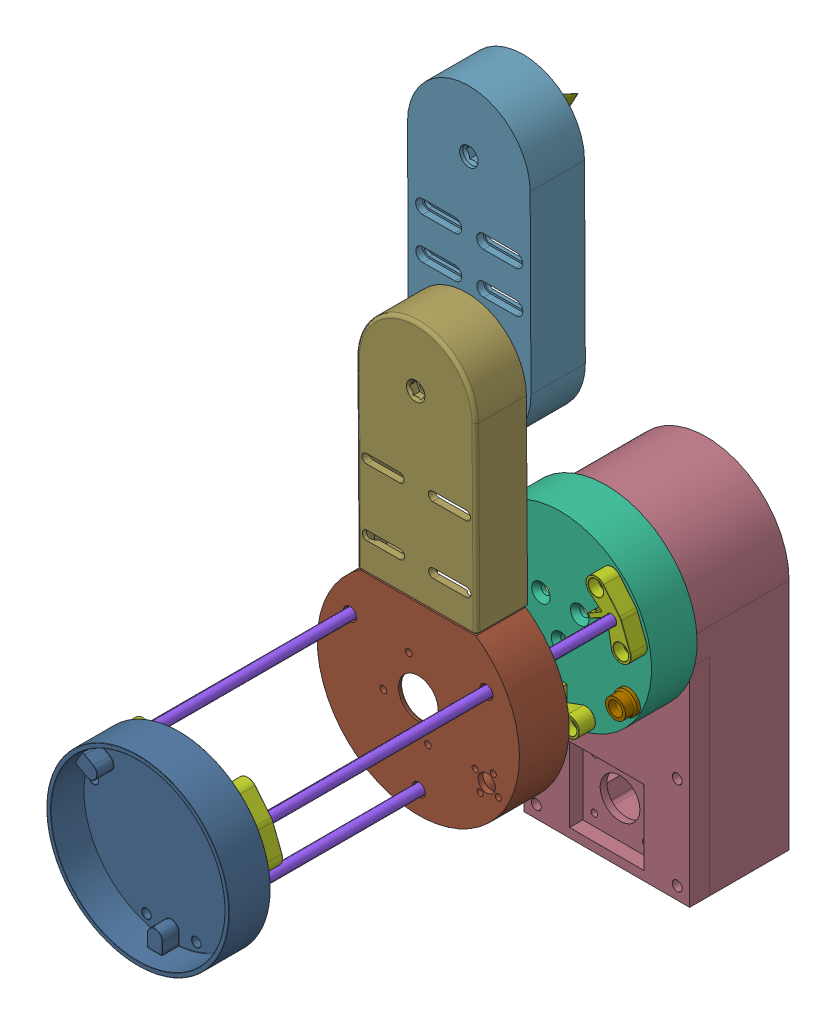
SolidWorks assembly Ensamblaje1 - copia, configuration Predeterminado. Lengths in mm.
Overall size (166.3 444.08 343).
26 component instances, 16 part files, 60 mates.
Components (placement in the parent):
- 4_Apoya rod rev2-1: 4_Apoya rod rev2 [Predeterminado] at (-2.0174 -4.7409 95) size (100 100 5)
- single direction thrust ball bearing_ks-1: single direction thrust ball bearing_ks [KS B 2022 ST - 51108-D] at (-2.0174 -4.7409 104.5) x (0.912212 -0.409718 0) z (0 0 -1) size (60 60 13)
- 3_sujeta_rod_sup rev2-1: 3_sujeta_rod_sup rev2 [Predeterminado] at (-2.0174 -4.7409 113) x (-0.50451 0.863406 0) z (0 0 -1) size (64 64 8)
- 4_Apoya rod rev2-2: 4_Apoya rod rev2 [Predeterminado] at (-2.0174 -4.7409 95) x (1 0 0) z (0 0 -1) size (100 100 5)
- single direction thrust ball bearing_ks-2: single direction thrust ball bearing_ks [KS B 2022 ST - 51108-D] at (-2.0174 -4.7409 85.5) x (0.272532 0.962147 0) z (0 0 1) size (60 60 13)
- 3_sujeta_rod_sup rev2-2: 3_sujeta_rod_sup rev2 [Predeterminado] at (-2.0174 -4.7409 77) x (-0.184869 -0.982763 0) z (0 0 1) size (64 64 8)
- 7_Espaciador 60T gt2-1: 7_Espaciador 60T gt2 [Predeterminado] at (-2.0174 -4.7409 71) x (0.20431 0.978906 0) z (0.978906 -0.20431 0) size (40 10 40)
- 6_Polea dentada 40-2: 6_Polea dentada 40 [Predeterminado] at (-2.0174 -4.7409 58.5) x (0.266472 -0.963843 0) z (0 0 1) size (40 40 12.5)
- 9_Base giratoria-1: 9_Base giratoria [Predeterminado] at (-2.0174 -4.7409 90.5) x (0.495477 0.868621 0) z (0 0 1) size (110 110 27.5)
- 11_Sosten varilla-1: 11_Sosten varilla [Predeterminado] at (-2.0174 -4.7409 93) x (-0.999986 -0.005215 0) z (0 0 1) size (42.08 20.32 10)
- 11_Sosten varilla-2: 11_Sosten varilla [Predeterminado] at (-2.0174 -4.7409 93) x (0.495477 0.868621 0) z (0 0 1) size (42.08 20.32 10)
- 11_Sosten varilla-3: 11_Sosten varilla [Predeterminado] at (-2.0174 -4.7409 93) x (0.50451 -0.863406 0) z (0 0 1) size (42.08 20.32 10)
- 18_Varilla altura-1: 18_Varilla altura [Predeterminado] at (38.7432 18.8499 108) x (0.998241 -0.059287 0) z (0 0 1) size (6 6 250)
- 18_Varilla altura-2: 18_Varilla altura [Predeterminado] at (-1.7697 -52.2402 108) x (0.999182 0.040445 0) z (0 0 1) size (6 6 250)
- 18_Varilla altura-3: 18_Varilla altura [Predeterminado] at (-43.2769 18.7943 108) x (0.846448 -0.532472 0) z (0 0 1) size (6 6 250)
- 13_Buje varilla roscada-1: 13_Buje varilla roscada [Predeterminado] at (39.2421 -28.276 118) x (0.23115 -0.972918 0) z (-0.972918 -0.23115 0) size (14 11 14)
- 9_Base giratoria superior-1: 9_Base giratoria superior [Predeterminado] at (-2.0174 -4.7409 373) x (-0.495477 -0.868621 0) z (0 0 -1) size (110 110 25)
- 11_Sosten varilla-4: 11_Sosten varilla [Predeterminado] at (-2.0174 -4.7409 373) x (-0.495477 -0.868621 0) z (0 0 -1) size (42.08 20.32 10)
- 11_Sosten varilla-5: 11_Sosten varilla [Predeterminado] at (-2.0174 -4.7409 373) x (-0.50451 0.863406 0) z (0 0 -1) size (42.08 20.32 10)
- 11_Sosten varilla-6: 11_Sosten varilla [Predeterminado] at (-2.0174 -4.7409 373) x (0.999986 0.005215 0) z (0 0 -1) size (42.08 20.32 10)
- 16_Carro-1: 16_Carro [Predeterminado] at (-2.0174 -4.7409 200.713) x (0.495477 0.868621 0) z (0 0 1) size (121.77 122 30.17)
- 17_Brazo carro - copia-1: 17_Brazo carro - copia [Predeterminado] at (-2.9277 45.1738 203.713) x (-0.99998 -0.006373 0) z (0 0 -1) size (72 146 30.8)
- 23_base final rev1 - copia-1: 23_base final rev1 - copia [Predeterminado] at (-2.0174 -4.7429 30) size (100 191 60)
- 19_Ultimo brazo-1: 19_Ultimo brazo [Predeterminado] at (-3.6106 151.1716 169.1497) x (-0.99999 -0.004545 0) z (0 0 -1) size (74 180 32.8)
- punta guia 3-1: punta guia 3 [Predeterminado] at (-4.1105 261.1704 145.1497) x (1 0 0) z (0 -1 0) size (30 10 30)
- punta guia 4-1: punta guia 4 [Predeterminado] at (-4.1105 261.1704 135.1497) x (1 0 0) z (0 -1 0) size (24 30 24)
Mates (geometry in assembly coordinates):
- Concéntrica31: concentric anti-aligned: circle of 4_Apoya rod rev2-1; circle of single direction thrust ball bearing_ks-1
- Coincidente51: coincident anti-aligned: plane of 4_Apoya rod rev2-1 through (-2.0174 -4.7409 98) normal (0 0 1); plane of single direction thrust ball bearing_ks-1 through (-14.3089 -32.1073 98) normal (0 0 -1)
- Concéntrica61: concentric anti-aligned: cylinder of 4_Apoya rod rev2-1 through (-2.0174 -4.7409 100) axis (0 0 -1) radius 19; cylinder of 3_sujeta_rod_sup rev2-1 through (-2.0174 -4.7409 108) axis (0 0 1) radius 7.5
- Coincidente71: coincident anti-aligned: plane of single direction thrust ball bearing_ks-1 through (-14.3089 -32.1073 111) normal (0 0 1); plane of 3_sujeta_rod_sup rev2-1 through (-2.0174 -4.7409 111) normal (0 0 -1)
- Concéntrica81: concentric anti-aligned: circle of 4_Apoya rod rev2-1; circle of 4_Apoya rod rev2-2
- Concéntrica91: concentric anti-aligned: cylinder of 4_Apoya rod rev2-1 through (-42.6204 -4.7409 87.2218) axis (0 0 1) radius 2.75; cylinder of 4_Apoya rod rev2-2 through (-42.6204 -4.7409 102.7782) axis (0 0 -1) radius 2.75
- Coincidente91: coincident anti-aligned: plane of 4_Apoya rod rev2-1 through (-2.0174 -4.7409 95) normal (0 0 -1); plane of 4_Apoya rod rev2-2 through (-2.0174 -4.7409 95) normal (0 0 1)
- Concéntrica101: concentric anti-aligned: circle of 4_Apoya rod rev2-2; circle of single direction thrust ball bearing_ks-2
- Coincidente101: coincident anti-aligned: plane of 4_Apoya rod rev2-2 through (-2.0174 -4.7409 92) normal (0 0 -1); plane of single direction thrust ball bearing_ks-2 through (-30.8818 3.4351 92) normal (0 0 1)
- Concéntrica111: concentric anti-aligned: cylinder of single direction thrust ball bearing_ks-2 through (-2.0174 -4.7409 104.459) axis (0 0 1) radius 20; cylinder of 3_sujeta_rod_sup rev2-2 through (-2.0174 -4.7409 82) axis (0 0 -1) radius 7.5
- Coincidente111: coincident anti-aligned: plane of single direction thrust ball bearing_ks-2 through (-30.8818 3.4351 79) normal (0 0 -1); plane of 3_sujeta_rod_sup rev2-2 through (-2.0174 -4.7409 79) normal (0 0 1)
- Concéntrica112: concentric anti-aligned: cylinder of 3_sujeta_rod_sup rev2-2 through (-2.0174 -4.7409 82) axis (0 0 -1) radius 7.5; cylinder of 7_Espaciador 60T gt2-1 through (-2.0174 -4.7409 71) axis (0 0 1) radius 6.6657
- Bloquear1: lock: unknown of 3_sujeta_rod_sup rev2-2; unknown of 7_Espaciador 60T gt2-1
- Concéntrica113: concentric aligned: circle of 7_Espaciador 60T gt2-1; circle of 6_Polea dentada 40-2
- Coincidente113: coincident anti-aligned: plane of 7_Espaciador 60T gt2-1 through (-2.0174 -4.7409 71) normal (0 0 -1); plane of 6_Polea dentada 40-2 through (-2.0174 -4.7409 71) normal (0 0 1)
- Bloquear2: lock: unknown of 7_Espaciador 60T gt2-1; unknown of 6_Polea dentada 40-2
- Coincidente117: coincident aligned: circle of 3_sujeta_rod_sup rev2-1; cylinder of 9_Base giratoria-1 through (-13.7438 1.948 118) axis (0 0 1) radius 2.75
- Concéntrica120: concentric anti-aligned: cylinder of 3_sujeta_rod_sup rev2-1 through (-1.947 -18.2407 120.7782) axis (0 0 -1) radius 2.75; cylinder of 9_Base giratoria-1 through (-1.947 -18.2407 118) axis (0 0 1) radius 2.75
- Coincidente118: coincident anti-aligned: plane of 3_sujeta_rod_sup rev2-1 through (-2.0174 -4.7409 113) normal (0 0 1); plane of 9_Base giratoria-1 through (-2.0174 -4.7409 113) normal (0 0 -1)
- Concéntrica121: concentric anti-aligned: cylinder of 9_Base giratoria-1 through (13.2211 -49.7509 113) axis (0 0 1) radius 1.75; cylinder of 11_Sosten varilla-1 through (13.2211 -49.7509 128) axis (0 0 -1) radius 2.95
- Concéntrica122: concentric anti-aligned: cylinder of 9_Base giratoria-1 through (-16.7856 -49.9074 113) axis (0 0 1) radius 1.75; cylinder of 11_Sosten varilla-1 through (-16.7856 -49.9074 128) axis (0 0 -1) radius 2.95
- Coincidente119: coincident anti-aligned: plane of 9_Base giratoria-1 through (-2.0174 -4.7409 118) normal (0 0 1); plane of 11_Sosten varilla-1 through (-2.0174 -4.7409 118) normal (0 0 -1)
- Concéntrica123: concentric anti-aligned: cylinder of 9_Base giratoria-1 through (-48.6165 4.5672 113) axis (0 0 1) radius 1.75; cylinder of 11_Sosten varilla-2 through (-48.6165 4.5672 128) axis (0 0 -1) radius 2.95
- Concéntrica124: concentric anti-aligned: cylinder of 9_Base giratoria-1 through (-33.7487 30.632 113) axis (0 0 1) radius 1.75; cylinder of 11_Sosten varilla-2 through (-33.7487 30.632 128) axis (0 0 -1) radius 2.95
- Coincidente120: coincident anti-aligned: plane of 9_Base giratoria-1 through (-2.0174 -4.7409 118) normal (0 0 1); plane of 11_Sosten varilla-2 through (-2.0174 -4.7409 118) normal (0 0 -1)
- Concéntrica125: concentric anti-aligned: cylinder of 9_Base giratoria-1 through (29.3432 30.961 113) axis (0 0 1) radius 1.75; cylinder of 11_Sosten varilla-3 through (29.3432 30.961 128) axis (0 0 -1) radius 2.95
- Concéntrica126: concentric anti-aligned: cylinder of 9_Base giratoria-1 through (44.4821 5.0527 113) axis (0 0 1) radius 1.75; cylinder of 11_Sosten varilla-3 through (44.4821 5.0527 128) axis (0 0 -1) radius 2.95
- Coincidente121: coincident anti-aligned: plane of 9_Base giratoria-1 through (-2.0174 -4.7409 118) normal (0 0 1); plane of 11_Sosten varilla-3 through (-2.0174 -4.7409 118) normal (0 0 -1)
- Concéntrica127: concentric aligned: cylinder of 11_Sosten varilla-3 through (38.7432 18.8499 128) axis (0 0 -1) radius 3; cylinder of 18_Varilla altura-1 through (38.7432 18.8499 358) axis (0 0 -1) radius 3
- Coincidente122: coincident anti-aligned: plane of 9_Base giratoria-1 through (38.9944 19.2233 108) normal (0 0 1); plane of 18_Varilla altura-1 through (38.7432 18.8499 108) normal (0 0 -1)
- Concéntrica128: concentric anti-aligned: cylinder of 9_Base giratoria-1 through (-1.7697 -52.2402 108) axis (0 0 1) radius 3; cylinder of 18_Varilla altura-2 through (-1.7697 -52.2402 358) axis (0 0 -1) radius 3
- Coincidente123: coincident anti-aligned: plane of 9_Base giratoria-1 through (-1.7697 -52.2402 108) normal (0 0 1); plane of 18_Varilla altura-2 through (-1.7697 -52.2402 108) normal (0 0 -1)
- Concéntrica129: concentric anti-aligned: cylinder of 9_Base giratoria-1 through (-43.2769 18.7943 108) axis (0 0 1) radius 3; cylinder of 18_Varilla altura-3 through (-43.2769 18.7943 358) axis (0 0 -1) radius 3
- Coincidente124: coincident anti-aligned: plane of 9_Base giratoria-1 through (-43.2769 18.7943 108) normal (0 0 1); plane of 18_Varilla altura-3 through (-43.2769 18.7943 108) normal (0 0 -1)
- Concéntrica130: concentric aligned: cylinder of 9_Base giratoria-1 through (39.2421 -28.276 108) axis (0 0 1) radius 4; cylinder of 13_Buje varilla roscada-1 through (39.2421 -28.276 115) axis (0 0 1) radius 3.75
- Coincidente125: coincident anti-aligned: plane of 9_Base giratoria-1 through (-2.0174 -4.7409 118) normal (0 0 1); plane of 13_Buje varilla roscada-1 through (39.2421 -28.276 118) normal (0 0 -1)
- Concéntrica135: concentric anti-aligned: circle of 13_Buje varilla roscada-1; cylinder of 9_Base giratoria superior-1 through (39.2421 -28.276 358) axis (0 0 -1) radius 4.25
- Concéntrica136: concentric aligned: cylinder of 18_Varilla altura-2 through (-1.7697 -52.2402 358) axis (0 0 -1) radius 3; cylinder of 9_Base giratoria superior-1 through (-1.7697 -52.2402 358) axis (0 0 -1) radius 3.25
- Coincidente128: coincident anti-aligned: plane of 18_Varilla altura-1 through (38.7432 18.8499 358) normal (0 0 1); plane of 9_Base giratoria superior-1 through (38.9944 19.2233 358) normal (0 0 -1)
- Concéntrica137: concentric anti-aligned: cylinder of 9_Base giratoria superior-1 through (-33.7487 30.632 353) axis (0 0 -1) radius 2.75; cylinder of 11_Sosten varilla-4 through (-33.7487 30.632 338) axis (0 0 1) radius 2.95
- Concéntrica138: concentric aligned: cylinder of 9_Base giratoria superior-1 through (-48.6165 4.5672 353) axis (0 0 -1) radius 2.75; cylinder of 11_Sosten varilla-4 through (-48.6165 4.5672 344) axis (0 0 -1) radius 4.6
- Coincidente129: coincident anti-aligned: plane of 9_Base giratoria superior-1 through (-2.0174 -4.7409 348) normal (0 0 -1); plane of 11_Sosten varilla-4 through (-2.0174 -4.7409 348) normal (0 0 1)
- Concéntrica139: concentric anti-aligned: cylinder of 11_Sosten varilla-5 through (29.3432 30.961 338) axis (0 0 1) radius 2.95; cylinder of 9_Base giratoria superior-1 through (29.3432 30.961 353) axis (0 0 -1) radius 2.75
- Concéntrica140: concentric aligned: circle of 9_Base giratoria superior-1; cylinder of 11_Sosten varilla-5 through (44.4821 5.0527 338) axis (0 0 1) radius 2.95
- Coincidente130: coincident anti-aligned: plane of 9_Base giratoria superior-1 through (-2.0174 -4.7409 348) normal (0 0 -1); plane of 11_Sosten varilla-5 through (-2.0174 -4.7409 348) normal (0 0 1)
- Concéntrica142: concentric anti-aligned: cylinder of 9_Base giratoria superior-1 through (-16.7856 -49.9074 353) axis (0 0 -1) radius 2.75; cylinder of 11_Sosten varilla-6 through (-16.7856 -49.9074 338) axis (0 0 1) radius 2.95
- Concéntrica143: concentric anti-aligned: cylinder of 9_Base giratoria superior-1 through (13.2211 -49.7509 353) axis (0 0 -1) radius 2.75; cylinder of 11_Sosten varilla-6 through (13.2211 -49.7509 338) axis (0 0 1) radius 2.95
- Coincidente131: coincident anti-aligned: plane of 9_Base giratoria superior-1 through (-2.0174 -4.7409 348) normal (0 0 -1); plane of 11_Sosten varilla-6 through (-2.0174 -4.7409 348) normal (0 0 1)
- Concéntrica144: concentric aligned: circle of 13_Buje varilla roscada-1; cylinder of 16_Carro-1 through (39.2421 -28.276 200.713) axis (0 0 1) radius 5.225
- Concéntrica145: concentric aligned: cylinder of 18_Varilla altura-2 through (-1.7697 -52.2402 358) axis (0 0 -1) radius 3; cylinder of 16_Carro-1 through (-1.7697 -52.2402 203.713) axis (0 0 -1) radius 4
- Concéntrica151: concentric anti-aligned: cylinder of 16_Carro-1 through (27.8491 25.3695 181.713) axis (-0.006373 0.99998 0) radius 2.75; cylinder of 17_Brazo carro - copia-1 through (27.3306 106.7239 181.713) axis (0.006373 -0.99998 0) radius 2.75
- Coincidente140: coincident anti-aligned: plane of 16_Carro-1 through (-2.2777 45.1779 200.713) normal (-0.006373 0.99998 0); plane of 17_Brazo carro - copia-1 through (32.0716 45.3968 199.713) normal (0.006373 -0.99998 0)
- Concéntrica152: concentric anti-aligned: cylinder of 4_Apoya rod rev2-2 through (-2.0174 35.8621 102.7782) axis (0 0 -1) radius 2.75; cylinder of 23_base final rev1 - copia-1 through (-2.0174 35.8621 30) axis (0 0 1) radius 3
- Coincidente141: coincident anti-aligned: plane of 4_Apoya rod rev2-2 through (-2.0174 -4.7409 90) normal (0 0 -1); plane of 23_base final rev1 - copia-1 through (-2.0174 -4.7429 90) normal (0 0 1)
- Coincidente146: coincident aligned: plane of 16_Carro-1 through (-2.0174 -4.7409 203.713) normal (0 0 1); plane of 17_Brazo carro - copia-1 through (-3.6287 155.1715 203.713) normal (0 0 1)
- Paralelo1: parallel anti-aligned: plane of 17_Brazo carro - copia-1 through (-3.6287 155.1715 199.713) normal (0 0 -1); plane of 19_Ultimo brazo-1 through (-3.6106 151.1716 171.1497) normal (0 0 1)
- Concéntrica155: concentric anti-aligned: cylinder of 17_Brazo carro - copia-1 through (-3.6287 155.1715 189.713) axis (0 0 1) radius 2.75; cylinder of 19_Ultimo brazo-1 through (-3.6287 155.1715 175.1497) axis (0 0 -1) radius 6.5
- Distancia1: distance = 10 mm: plane of punta guia 3-1 through (-16.1552 261.1704 145.1497) normal (0 0 1); plane of 19_Ultimo brazo-1 through (-3.6106 151.1716 155.1497) normal (0 0 -1)
- Concéntrica156: concentric anti-aligned: cylinder of 19_Ultimo brazo-1 through (-4.1105 261.1704 171.1497) axis (0 0 -1) radius 5.6; cylinder of punta guia 3-1 through (-4.1105 261.1704 135.1497) axis (0 0 1) radius 2.55
- Coincidente148: coincident anti-aligned: circle of punta guia 3-1; circle of punta guia 4-1
